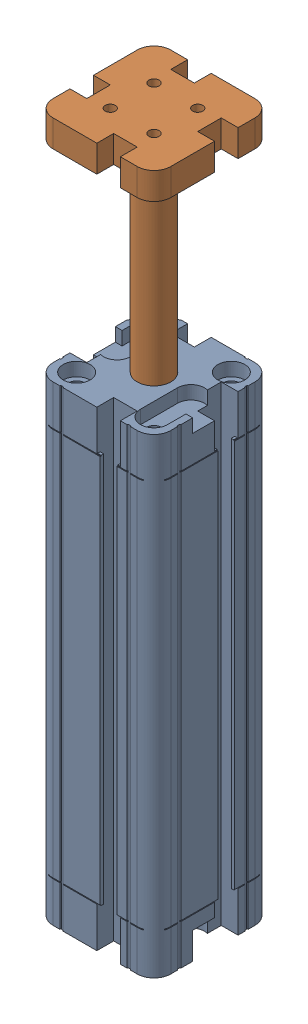
SolidWorks assembly Cylinder 140mm Assembled, configuration Default. Lengths in mm.
Overall size (35 208 35).
2 component instances, 2 part files, 2 mates.
Components (placement in the parent):
- 11.5cm Cylinder-1: 11.5cm Cylinder [Default] at (-34.2 -59.3514 58.3694) size (35 140 35)
- Cylinder Rod 110mm-1: Cylinder Rod 110mm [Default] at (-34.2 140.6486 58.3694) size (35 110 35)
Mates (geometry in assembly coordinates):
- Concentric1: concentric: cylinder of 11.5cm Cylinder-1 through (-16.7 -59.3524 40.8694) axis (0 1 0) radius 5; cylinder of Cylinder Rod 110mm-1 through (-16.7 3.1437 40.8694) axis (0 1 0) radius 5
- Distance1: distance = 60 mm anti-aligned: plane of Cylinder Rod 110mm-1 through (-34.2 140.6486 58.3694) normal (0 -1 0); plane of 11.5cm Cylinder-1 through (-34.2 80.6486 58.3694) normal (0 1 0)
